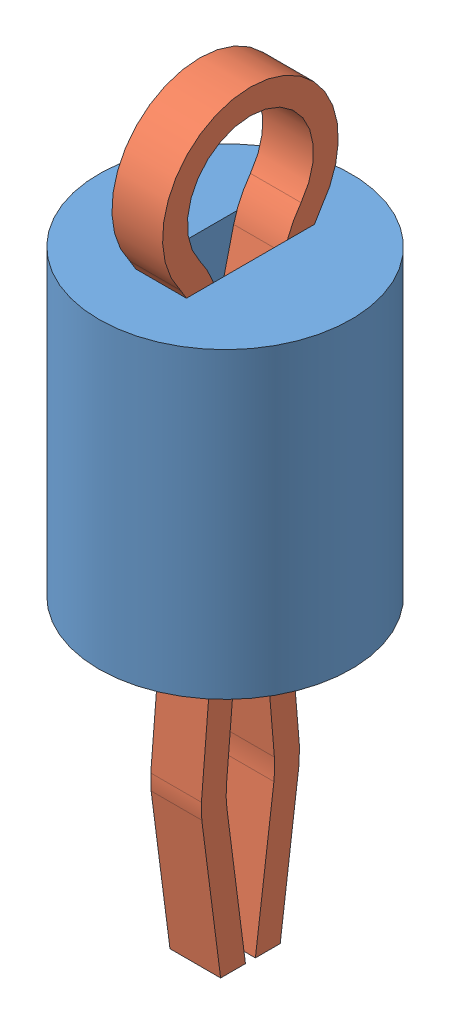
SolidWorks assembly Assem1, configuration Default. Lengths in mm.
Overall size (2.54 7.62 2.54).
2 component instances, 2 part files, 6 mates.
Components (placement in the parent):
- Spacer-white-1: Spacer-white [Default] x (0 0 1) z (0 1 0) size (2.54 2.54 3.05)
- Contact-1: Contact [Default] x (0 0 -1) z (0 1 0) size (1.77 0.51 7.62)
Mates (geometry in assembly coordinates):
- Coincident1: coincident aligned: plane of Spacer-white-1 through (0 0 0) normal (1 0 0)
- Coincident2: coincident aligned: plane of Spacer-white-1 through (0 0 0) normal (0 0 1)
- Coincident3: coincident anti-aligned: plane of Spacer-white-1 through (0 0 0) normal (0 -1 0)
- Coincident4: coincident anti-aligned: plane of Contact-1 through (0 0 0) normal (-1 0 0)
- Coincident5: coincident anti-aligned: plane of Contact-1 through (0 0 0) normal (0 0 -1)
- Distance1: distance = 3.05 mm aligned: plane of Contact-1 through (0 -3.05 0.175) normal (0 -1 0); plane of Spacer-white-1 through (0 0 0) normal (0 -1 0)
